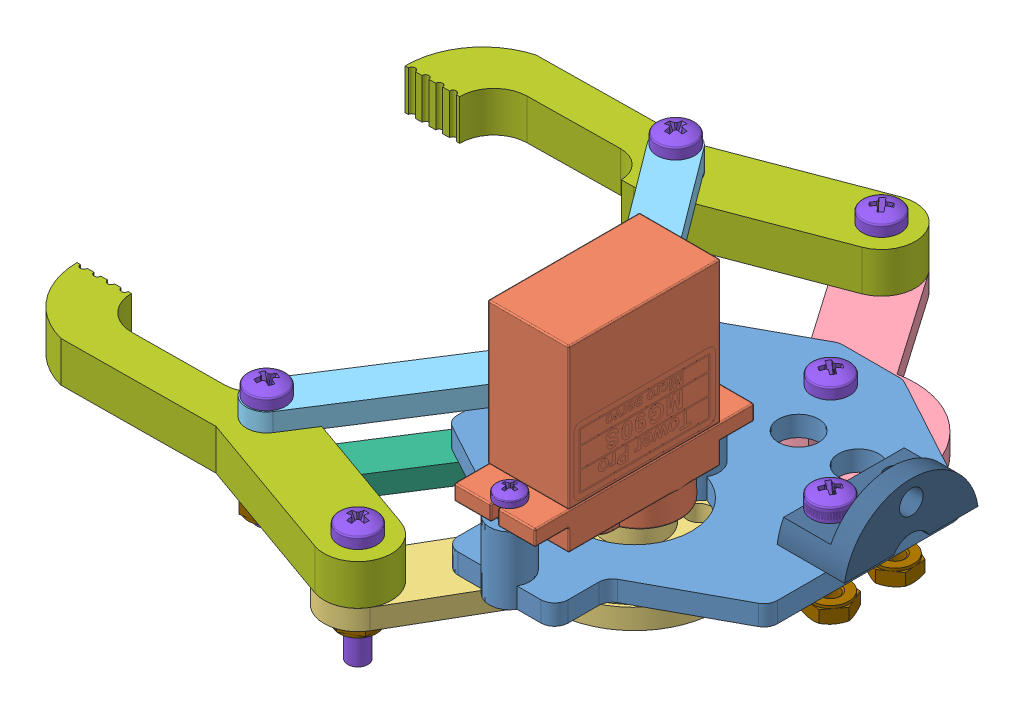
SolidWorks assembly CLAWl, configuration По умолчанию. Lengths in mm.
Overall size (99.28 46.3 101.52).
32 component instances, 10 part files, 64 mates.
Components (placement in the parent):
- plate-1: plate [По умолчанию] at origin size (47.5 10 56.6)
- MG90s_servo-1: MG90s_servo [Default] at (0 12.3 4.5) x (0 0 -1) z (0 1 0) size (32.5 12 34)
- rightGear-1: rightGear [По умолчанию] at (0 -5.2 0) x (0.501925 0 -0.864911) z (0.864911 0 0.501925) size (49 8 26.5)
- leftGear-1: leftGear [По умолчанию] at (0 -3 -29.1) x (0.570522 0 0.821282) z (0.821282 0 -0.570522) size (49 6 26.5)
- clawRearBar-1: clawRearBar [По умолчанию] at (-38.7879 6.5 -44.9139) x (0.597762 0 0.801674) z (0.801674 0 -0.597762) size (38.2 4 6)
- clawFrontBar-1: clawFrontBar [По умолчанию] at (-19.54 -6 -19.1) x (-0.597762 0 -0.801674) z (0.801674 0 -0.597762) size (38.2 6 6)
- clawGripper-1: clawGripper [По умолчанию] at (-68.4865 -3 -38.5147) x (0.99991 0 -0.013423) z (0.013423 0 0.99991) size (60.56 6 19.53)
- clawRearBar-2: clawRearBar [По умолчанию] at (-36.9207 6.5 17.6063) x (0.539772 0 -0.841811) z (-0.841811 0 -0.539772) size (38.2 4 6)
- clawGripper-2: clawGripper [По умолчанию] at (-66.754 3.8 11.8683) x (0.999961 0 -0.00879) z (-0.00879 0 -0.999961) size (60.56 6 19.53)
- clawFrontBar-2: clawFrontBar [По умолчанию] at (-19.54 -6 -9.5) x (-0.539772 0 0.841811) z (-0.841811 0 -0.539772) size (38.2 6 6)
- pan head cross recess screw_iso-1: pan head cross recess screw_iso [ISO 7045 - M3 x 16 - Z - 16N] at (-19.54 8.9 -19.1) x (0 -1 0) z (0.546944 0 -0.837169) size (18.35 5.6 5.6)
- pan head cross recess screw_iso-2: pan head cross recess screw_iso [ISO 7045 - M3 x 16 - Z - 16N] at (-19.54 8.9 -9.5) x (0 -1 0) z (0 0 1) size (18.35 5.6 5.6)
- pan head cross recess screw_iso-4: pan head cross recess screw_iso [ISO 7045 - M3 x 16 - Z - 16N] at (-38.7879 8.9 -44.9139) x (0 -1 0) z (0 0 1) size (18.35 5.6 5.6)
- pan head cross recess screw_iso-5: pan head cross recess screw_iso [ISO 7045 - M3 x 16 - Z - 16N] at (0 5.4 -29.1) x (0 -1 0) z (0.546944 0 -0.837169) size (18.35 5.6 5.6)
- pan head cross recess screw_iso-7: pan head cross recess screw_iso [ISO 7045 - M3 x 16 - Z - 16N] at (-15.0577 6.2 25.9473) x (0 -1 0) z (0 0 1) size (18.35 5.6 5.6)
- pan head cross recess screw_iso-8: pan head cross recess screw_iso [ISO 7045 - M3 x 16 - Z - 16N] at (-36.9207 8.9 17.6063) x (0 -1 0) z (0.928142 0 0.372226) size (18.35 5.6 5.6)
- pan head cross recess screw_iso-11: pan head cross recess screw_iso [ISO 7045 - M3 x 16 - Z - 16N] at (-17.1157 5.4 -53.7385) x (0 -1 0) z (0.652123 0 0.758113) size (18.35 5.6 5.6)
- pan head cross recess screw_iso-12: pan head cross recess screw_iso [ISO 7045 - M3 x 16 - Z - 16N] at (0 -7.6 0) x (0 1 0) z (0 0 1) size (18.35 5.6 5.6)
- pan head cross recess screw_iso-13: pan head cross recess screw_iso [ISO 7045 - M2 x 12 - Z - 12N] at (0 13.9 18.5) x (0 -1 0) z (0 0 1) size (13.57 4 4)
- pan head cross recess screw_iso-14: pan head cross recess screw_iso [ISO 7045 - M2 x 5 - Z - 5N] at (0 13.9 -9.5) x (0 -1 0) z (-0.924225 0 0.381849) size (6.57 4 4)
- hex nut style 1 gradeab_iso-1: hex nut style 1 gradeab_iso [ISO - 4032 - M3 - W - N] at (-17.1157 -6 -53.7385) x (1 0 0) z (0 1 0) size (5.5 6.35 2.4)
- hex nut style 1 gradeab_iso-2: hex nut style 1 gradeab_iso [ISO - 4032 - M3 - W - N] at (-38.7879 -8.4 -44.9139) x (1 0 0) z (0 -1 0) size (5.5 6.35 2.4)
- hex nut style 1 gradeab_iso-3: hex nut style 1 gradeab_iso [ISO - 4032 - M3 - W - N] at (0 -6 -29.1) x (1 0 0) z (0 1 0) size (5.5 6.35 2.4)
- hex nut style 1 gradeab_iso-4: hex nut style 1 gradeab_iso [ISO - 4032 - M3 - W - N] at (-19.54 -6 -9.5) x (1 0 0) z (0 1 0) size (5.5 6.35 2.4)
- hex nut style 1 gradeab_iso-5: hex nut style 1 gradeab_iso [ISO - 4032 - M3 - W - N] at (-36.9207 -5.8392 17.6063) x (0.929311 0 0.369298) z (0 1 0) size (5.5 6.35 2.4)
- hex nut style 1 gradeab_iso-6: hex nut style 1 gradeab_iso [ISO - 4032 - M3 - W - N] at (-19.54 -9.5 -19.1) x (0.981291 0 -0.192532) z (0 -1 0) size (5.5 6.35 2.4)
- hex nut style 1 gradeab_iso-7: hex nut style 1 gradeab_iso [ISO - 4032 - M3 - W - N] at (-15.0577 -5.2 25.9473) x (1 0 0) z (0 1 0) size (5.5 6.35 2.4)
- hex nut style 1 gradeab_iso-8: hex nut style 1 gradeab_iso [ISO - 4032 - M3 - W - N] at (19.54 -6.25 -19.1) x (-0.996863 0 0.079145) z (0 -1 0) size (5.5 6.35 2.4)
- hex nut style 1 gradeab_iso-9: hex nut style 1 gradeab_iso [ISO - 4032 - M3 - W - N] at (19.54 -6.25 -9.5) x (0.92134 0 -0.388758) z (0 -1 0) size (5.5 6.35 2.4)
- pan head cross recess screw_iso-15: pan head cross recess screw_iso [ISO 7045 - M3 x 8 - Z - 8N] at (19.54 9.1168 -9.5) x (0 -1 0) z (-0.751781 0 -0.659413) size (10.35 5.6 5.6)
- pan head cross recess screw_iso-16: pan head cross recess screw_iso [ISO 7045 - M3 x 8 - Z - 8N] at (19.54 9.55 -9.5) x (0 -1 0) z (-0.546944 0 0.837169) size (10.35 5.6 5.6)
- clawBase-1: clawBase [По умолчанию] at (16.54 1.5 -14.5) x (0 0 -1) z (0 -1 0) size (19.77 10 8.5)
Mates (geometry in assembly coordinates):
- Совпадение1: coincident anti-aligned: plane of plate-1 through (0 10 18.5) normal (0 1 0); plane of MG90s_servo-1 through (0 10 4.5) normal (0 -1 0)
- Концентричный1: concentric aligned: cylinder of plate-1 through (0 0 18.5) axis (0 1 0) radius 1.4; cylinder of MG90s_servo-1 through (0 10 18.5) axis (0 1 0) radius 1
- Концентричный2: concentric aligned: cylinder of plate-1 through (0 0 -9.5) axis (0 1 0) radius 1.4; cylinder of MG90s_servo-1 through (0 10 -9.5) axis (0 1 0) radius 1
- Совпадение2: coincident anti-aligned: plane of MG90s_servo-1 through (0 2.8 5.75) normal (0 -1 0); plane of rightGear-1 through (0 2.8 0) normal (0 1 0)
- Концентричный3: concentric aligned: cylinder of plate-1 through (0 3 0) axis (0 -1 0) radius 8.5; cylinder of rightGear-1 through (0 2.8 0) axis (0 -1 0) radius 4.5
- Совпадение3: coincident anti-aligned: plane of plate-1 through (0 0 0) normal (0 -1 0); plane of leftGear-1 through (0 0 -29.1) normal (0 1 0)
- Концентричный4: concentric aligned: circle of plate-1; cylinder of leftGear-1 through (0 -6 -29.1) axis (0 1 0) radius 1.75
- Совпадение22: coincident anti-aligned: plane of leftGear-1 through (12.6818 -3 -23.1695) normal (0 1 0); plane of clawGripper-1 through (-61.0894 -3 -38.614) normal (0 -1 0)
- Концентричный23: concentric aligned: cylinder of leftGear-1 through (-17.1157 -6 -53.7385) axis (0 1 0) radius 1.75; circle of clawGripper-1
- Концентричный26: concentric aligned: circle of plate-1; circle of clawFrontBar-1
- Концентричный27: concentric anti-aligned: circle of clawFrontBar-1; cylinder of clawGripper-1 through (-38.7879 3 -44.9139) axis (0 -1 0) radius 1.75
- Совпадение28: coincident anti-aligned: plane of plate-1 through (0 3 0) normal (0 1 0); plane of clawRearBar-1 through (-19.54 3 -19.1) normal (0 -1 0)
- Концентричный30: concentric anti-aligned: circle of plate-1; circle of clawRearBar-1
- Концентричный31: concentric aligned: cylinder of clawRearBar-1 through (-38.7879 6.5 -44.9139) axis (0 -1 0) radius 1.75; cylinder of clawGripper-1 through (-38.7879 3 -44.9139) axis (0 -1 0) radius 1.75
- Совпадение29: coincident anti-aligned: plane of plate-1 through (0 3 0) normal (0 1 0); plane of clawRearBar-2 through (-19.54 3 -9.5) normal (0 -1 0)
- Концентричный32: concentric aligned: cylinder of plate-1 through (-19.54 3 -9.5) axis (0 -1 0) radius 1.4; cylinder of clawRearBar-2 through (-19.54 6.5 -9.5) axis (0 -1 0) radius 1.75
- Совпадение30: coincident anti-aligned: plane of rightGear-1 through (12.1582 -2.2 -6.9411) normal (0 1 0); plane of clawGripper-2 through (-59.3566 -2.2 11.8033) normal (0 -1 0)
- Концентричный33: concentric anti-aligned: cylinder of rightGear-1 through (-15.0577 -2.2 25.9473) axis (0 -1 0) radius 1.75; cylinder of clawGripper-2 through (-15.0577 -2.2 25.9473) axis (0 1 0) radius 1.75
- Концентричный34: concentric anti-aligned: cylinder of clawRearBar-2 through (-36.9207 6.5 17.6063) axis (0 -1 0) radius 1.75; cylinder of clawGripper-2 through (-36.9207 -2.2 17.6063) axis (0 1 0) radius 1.75
- Совпадение32: coincident anti-aligned: plane of plate-1 through (0 0 0) normal (0 -1 0); plane of clawFrontBar-2 through (-19.54 0 -9.5) normal (0 1 0)
- Концентричный35: concentric anti-aligned: cylinder of plate-1 through (-19.54 3 -9.5) axis (0 -1 0) radius 1.4; cylinder of clawFrontBar-2 through (-19.54 -6 -9.5) axis (0 1 0) radius 1.75
- Концентричный36: concentric aligned: cylinder of clawGripper-2 through (-36.9207 -2.2 17.6063) axis (0 1 0) radius 1.75; cylinder of clawFrontBar-2 through (-36.9207 -6 17.6063) axis (0 1 0) radius 1.75
- Сопряжения редуктора1: gear = 28 : 28 mm: circle of leftGear-1; circle of rightGear-1
- Параллельность3: parallel aligned: plane of rightGear-1 through (12.1582 -5.2 -6.9411) normal (0 -1 0); plane of leftGear-1 through (12.6818 -6 -23.1695) normal (0 -1 0)
- Параллельность4: parallel aligned: plane of rightGear-1 through (12.1582 -5.2 -6.9411) normal (0 -1 0); plane of leftGear-1 through (12.6818 -6 -23.1695) normal (0 -1 0)
- Концентричный37: concentric anti-aligned: circle of rightGear-1; cylinder of pan head cross recess screw_iso-12 through (0 -33 0) axis (0 -1 0) radius 1.5
- Совпадение33: coincident anti-aligned: plane of rightGear-1 through (12.1582 -5.2 -6.9411) normal (0 -1 0); plane of pan head cross recess screw_iso-12 through (-1.5 -5.2 0) normal (0 1 0)
- Концентричный38: concentric anti-aligned: circle of clawRearBar-1; circle of pan head cross recess screw_iso-1
- Совпадение34: coincident anti-aligned: plane of clawRearBar-1 through (-38.7879 6.5 -44.9139) normal (0 1 0); plane of pan head cross recess screw_iso-1 through (-20.7958 6.5 -19.9204) normal (0 -1 0)
- Концентричный39: concentric anti-aligned: circle of clawRearBar-2; circle of pan head cross recess screw_iso-2
- Совпадение35: coincident anti-aligned: plane of clawRearBar-2 through (-36.9207 6.5 17.6063) normal (0 1 0); plane of pan head cross recess screw_iso-2 through (-18.04 6.5 -9.5) normal (0 -1 0)
- Концентричный40: concentric anti-aligned: circle of clawGripper-2; circle of pan head cross recess screw_iso-7
- Совпадение36: coincident anti-aligned: plane of clawGripper-2 through (-59.3566 3.8 11.8033) normal (0 1 0); plane of pan head cross recess screw_iso-7 through (-13.5577 3.8 25.9473) normal (0 -1 0)
- Концентричный41: concentric anti-aligned: circle of clawRearBar-2; circle of pan head cross recess screw_iso-8
- Совпадение37: coincident anti-aligned: plane of clawRearBar-2 through (-36.9207 6.5 17.6063) normal (0 1 0); plane of pan head cross recess screw_iso-8 through (-36.3623 6.5 16.2141) normal (0 -1 0)
- Концентричный42: concentric anti-aligned: circle of clawRearBar-1; circle of pan head cross recess screw_iso-4
- Параллельность5: parallel anti-aligned: plane of clawRearBar-1 through (-38.7879 6.5 -44.9139) normal (0 1 0); plane of pan head cross recess screw_iso-4 through (-37.2879 6.5 -44.9139) normal (0 -1 0)
- Совпадение40: coincident anti-aligned: plane of clawRearBar-1 through (-38.7879 6.5 -44.9139) normal (0 1 0); plane of pan head cross recess screw_iso-4 through (-37.2879 6.5 -44.9139) normal (0 -1 0)
- Концентричный43: concentric aligned: circle of clawGripper-1; circle of pan head cross recess screw_iso-11
- Совпадение41: coincident anti-aligned: plane of clawGripper-1 through (-61.0894 3 -38.614) normal (0 1 0); plane of pan head cross recess screw_iso-11 through (-15.9785 3 -54.7167) normal (0 -1 0)
- Концентричный45: concentric aligned: circle of plate-1; circle of pan head cross recess screw_iso-5
- Совпадение42: coincident anti-aligned: plane of pan head cross recess screw_iso-5 through (-1.2558 3 -29.9204) normal (0 -1 0); plane of plate-1 through (0 3 0) normal (0 1 0)
- Концентричный46: concentric anti-aligned: circle of MG90s_servo-1; circle of pan head cross recess screw_iso-13
- Совпадение43: coincident anti-aligned: plane of MG90s_servo-1 through (0 12.3 4.5) normal (0 1 0); plane of pan head cross recess screw_iso-13 through (1 12.3 18.5) normal (0 -1 0)
- Концентричный47: concentric anti-aligned: circle of MG90s_servo-1; circle of pan head cross recess screw_iso-14
- Совпадение44: coincident anti-aligned: plane of MG90s_servo-1 through (0 12.3 4.5) normal (0 1 0); plane of pan head cross recess screw_iso-14 through (0.3818 12.3 -8.5758) normal (0 -1 0)
- Концентричный48: concentric anti-aligned: circle of pan head cross recess screw_iso-11; circle of hex nut style 1 gradeab_iso-1
- Совпадение45: coincident anti-aligned: plane of leftGear-1 through (12.6818 -6 -23.1695) normal (0 -1 0); plane of hex nut style 1 gradeab_iso-1 through (-17.1157 -6 -56.9139) normal (0 1 0)
- Концентричный49: concentric aligned: circle of pan head cross recess screw_iso-4; circle of hex nut style 1 gradeab_iso-2
- Совпадение46: coincident anti-aligned: plane of clawFrontBar-1 through (-19.54 -6 -19.1) normal (0 -1 0); plane of hex nut style 1 gradeab_iso-2 through (-38.7879 -6 -41.7385) normal (0 1 0)
- Концентричный50: concentric anti-aligned: circle of pan head cross recess screw_iso-5; circle of hex nut style 1 gradeab_iso-3
- Совпадение47: coincident anti-aligned: plane of leftGear-1 through (12.6818 -6 -23.1695) normal (0 -1 0); plane of hex nut style 1 gradeab_iso-3 through (0 -6 -32.2754) normal (0 1 0)
- Концентричный51: concentric anti-aligned: circle of pan head cross recess screw_iso-2; circle of hex nut style 1 gradeab_iso-4
- Концентричный52: concentric anti-aligned: circle of pan head cross recess screw_iso-8; circle of hex nut style 1 gradeab_iso-5
- Совпадение48: coincident anti-aligned: circle of pan head cross recess screw_iso-1; circle of hex nut style 1 gradeab_iso-6
- Концентричный53: concentric anti-aligned: circle of pan head cross recess screw_iso-7; circle of hex nut style 1 gradeab_iso-7
- Совпадение49: coincident anti-aligned: plane of clawFrontBar-2 through (-19.54 -6 -9.5) normal (0 -1 0); plane of hex nut style 1 gradeab_iso-4 through (-19.54 -6 -12.6754) normal (0 1 0)
- Совпадение50: coincident anti-aligned: plane of rightGear-1 through (12.1582 -5.2 -6.9411) normal (0 -1 0); plane of hex nut style 1 gradeab_iso-7 through (-15.0577 -5.2 22.7719) normal (0 1 0)
- Концентричный58: concentric anti-aligned: circle of hex nut style 1 gradeab_iso-9; circle of pan head cross recess screw_iso-16
- Concentric1: concentric anti-aligned: cylinder of pan head cross recess screw_iso-15 through (19.54 34.5168 -9.5) axis (0 1 0) radius 1.5; cylinder of clawBase-1 through (19.54 10 -9.5) axis (0 -1 0) radius 1.75
- Parallel2: parallel anti-aligned: plane of plate-1 through (0 3 0) normal (0 1 0); plane of clawBase-1 through (26.54 3 -2.1179) normal (0 -1 0)
- Coincident1: coincident anti-aligned: plane of plate-1 through (0 3 0) normal (0 1 0); plane of clawBase-1 through (26.54 3 -2.1179) normal (0 -1 0)
- Concentric2: concentric anti-aligned: circle of plate-1; circle of clawBase-1
- Parallel3: parallel aligned: plane of MG90s_servo-1 through (6 33.3 15.75) normal (1 0 0); plane of clawBase-1 through (26.54 1.5 -14.5) normal (1 0 0)
